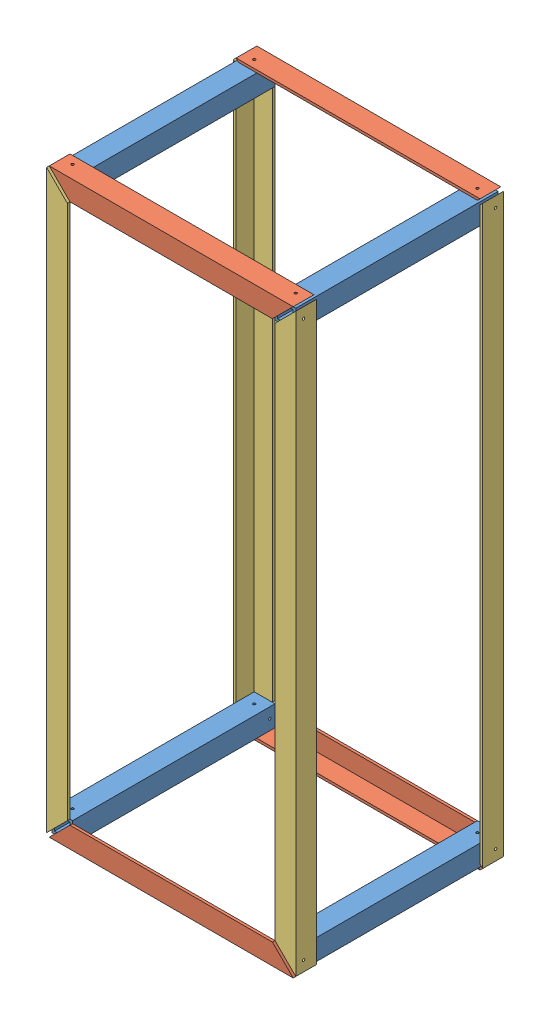
SolidWorks assembly Assem3, configuration Default. Lengths in mm.
Overall size (304.8 711.2 254).
12 component instances, 3 part files, 23 mates.
Components (placement in the parent):
- box bar-1: box bar [Default] at (208.2281 57.5583 -264.8648) size (25.4 25.4 247.65)
- box bar-2: box bar [Default] at (481.2781 737.0083 -264.8648) size (25.4 25.4 247.65)
- box bar-3: box bar [Default] at (208.2281 737.0083 -264.8648) size (25.4 25.4 247.65)
- box bar-4: box bar [Default] at (481.2781 57.5583 -264.8648) size (25.4 25.4 247.65)
- L angle 12 INH-1: L angle 12 INH [Default] at (493.9781 41.6833 -268.0398) x (0 0 1) z (-1 0 0) size (25.4 25.4 298.45)
- L angle 28 INH-1: L angle 28 INH [Default] at (192.3531 44.8583 -268.0398) x (0 0 1) z (0 1 0) size (25.4 25.4 704.85)
- L angle 12 INH-2: L angle 12 INH [Default] at (195.5281 752.8833 -268.0398) x (0 0 1) z (1 0 0) size (25.4 25.4 298.45)
- L angle 12 INH-3: L angle 12 INH [Default] at (195.5281 41.6833 -14.0398) x (0 0 -1) z (1 0 0) size (25.4 25.4 298.45)
- L angle 12 INH-4: L angle 12 INH [Default] at (493.9781 752.8833 -14.0398) x (0 0 -1) z (-1 0 0) size (25.4 25.4 298.45)
- L angle 28 INH-2: L angle 28 INH [Default] at (497.1531 44.8583 -14.0398) x (0 0 -1) z (0 1 0) size (25.4 25.4 704.85)
- L angle 28 INH-3: L angle 28 INH [Default] at (192.3531 749.7083 -14.0398) x (0 0 -1) z (0 -1 0) size (25.4 25.4 704.85)
- L angle 28 INH-4: L angle 28 INH [Default] at (497.1531 749.7083 -268.0398) x (0 0 1) z (0 -1 0) size (25.4 25.4 704.85)
Mates (geometry in assembly coordinates):
- Parallel1: parallel aligned: plane of box bar-1 through (220.9281 44.8583 -17.2148) normal (1 0 0); plane of box bar-3 through (220.9281 724.3083 -17.2148) normal (1 0 0)
- Coincident2: coincident aligned: line of box bar-1 through (220.9281 44.8583 -264.8648) axis (0 1 0); line of box bar-3 through (220.9281 724.3083 -264.8648) axis (0 1 0)
- Coincident3: coincident aligned: line of box bar-1 through (195.5281 44.8583 -264.8648) axis (1 0 0); line of box bar-4 through (468.5781 44.8583 -264.8648) axis (1 0 0)
- Coincident4: coincident aligned: line of box bar-2 through (468.5781 724.3083 -264.8648) axis (1 0 0); line of box bar-3 through (195.5281 724.3083 -264.8648) axis (1 0 0)
- Coincident6: coincident aligned: plane of box bar-1 through (195.5281 44.8583 -17.2148) normal (0 -1 0); plane of box bar-4 through (468.5781 44.8583 -17.2148) normal (0 -1 0)
- Parallel2: parallel aligned: line of box bar-1 through (195.5281 44.8583 -264.8648) axis (1 0 0); line of L angle 12 INH-1 through (198.7031 44.8583 -264.8648) axis (1 0 0)
- Parallel3: parallel anti-aligned: plane of box bar-4 through (468.5781 44.8583 -17.2148) normal (0 -1 0); plane of L angle 12 INH-1 through (195.5281 44.8583 -242.6398) normal (0 1 0)
- Coincident10: coincident anti-aligned: circle of box bar-4; circle of L angle 12 INH-1
- Coincident11: coincident anti-aligned: circle of box bar-1; circle of L angle 12 INH-1
- Concentric3: concentric aligned: circle of box bar-3; circle of L angle 12 INH-2
- Coincident13: coincident aligned: circle of box bar-2; circle of L angle 12 INH-2
- Coincident14: coincident anti-aligned: circle of box bar-4; circle of L angle 12 INH-3
- Coincident15: coincident anti-aligned: circle of box bar-1; circle of L angle 12 INH-3
- Coincident16: coincident aligned: circle of box bar-3; circle of L angle 12 INH-4
- Coincident17: coincident aligned: circle of box bar-2; circle of L angle 12 INH-4
- Concentric4: concentric anti-aligned: circle of box bar-3; circle of L angle 28 INH-1
- Coincident19: coincident anti-aligned: circle of box bar-1; circle of L angle 28 INH-1
- Concentric5: concentric aligned: circle of box bar-4; circle of L angle 28 INH-4
- Coincident21: coincident aligned: circle of box bar-2; circle of L angle 28 INH-4
- Coincident22: coincident aligned: circle of box bar-4; circle of L angle 28 INH-2
- Coincident23: coincident aligned: cylinder of box bar-2 through (239.9781 737.0083 -23.5648) axis (1 0 0) radius 1.5; circle of L angle 28 INH-2
- Coincident25: coincident anti-aligned: circle of box bar-3; circle of L angle 28 INH-3
- Coincident26: coincident anti-aligned: circle of box bar-1; circle of L angle 28 INH-3
